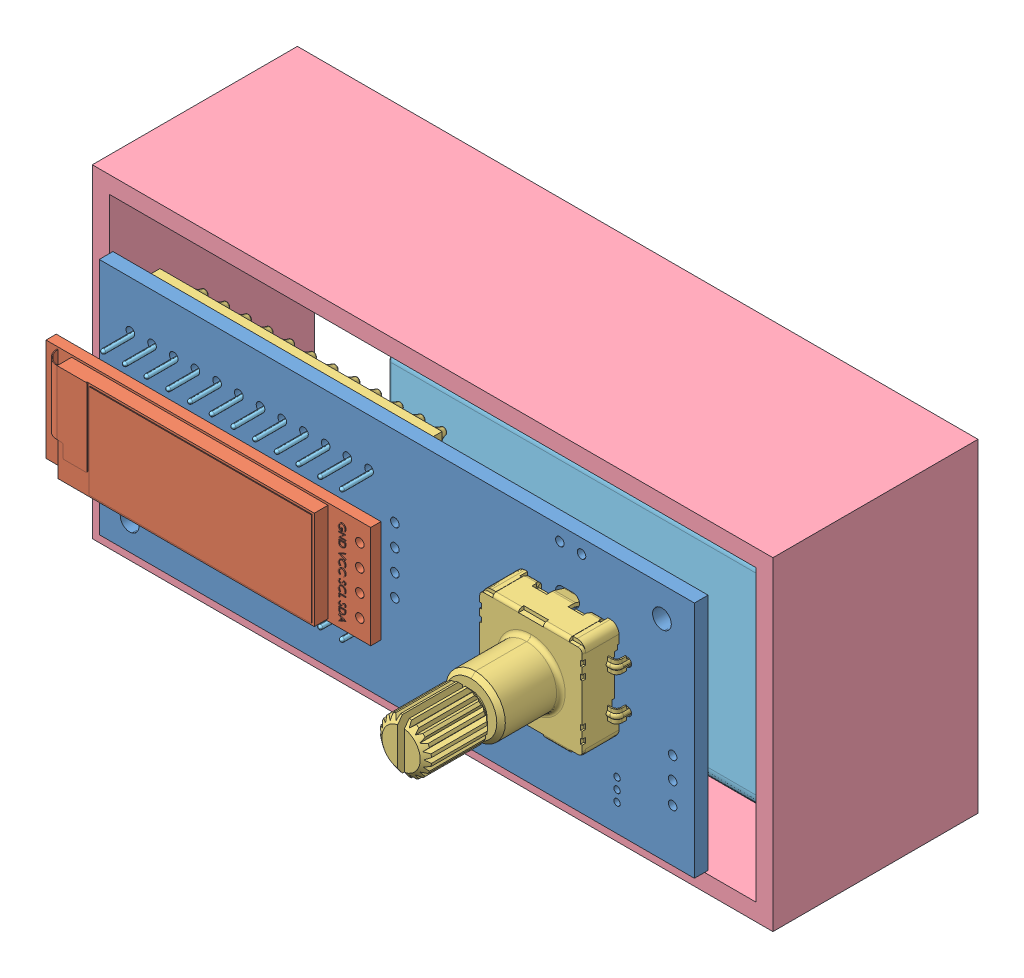
SolidWorks assembly IntervalometerFullAssembly, configuration Default. Lengths in mm.
Overall size (79.65 37.9 47.73).
70 component instances, 27 part files, 2 mates.
Components (placement in the parent):
- BoardAssembly-1: BoardAssembly [Default] at (-53.0981 -17.4336 -57.1402) size (71.78 27.9 29.29)
  - CameraIntervalometer.step-1: CameraIntervalometer.step [Default] at (-116.9591 121.2017 48.7284) size (69.65 27.9 1.6)
    - _autosave-CameraIntervalometer PCB.step-1: _autosave-CameraIntervalometer PCB.step [Default] at origin size (69.65 27.9 1.6)
  - 128x32-OLED-1: 128x32-OLED [Default] at (13.1078 38.9667 53.2284) x (-1 0 0) z (0 0 1) size (38 12 2.96)
  - ARDUINO PRO MICRO.IGS-1: ARDUINO PRO MICRO.IGS [Default] at (0.0509 46.4031 44.8284) x (1 0 0) z (0 1 0) size (34.6 13.31 17.79)
    - micro board.IGS-1: micro board.IGS [Default] at origin size (33.03 3.11 17.79)
    - MICRO_stackable header 12.IGS-1: MICRO_stackable header 12.IGS [Default] at (0 -3.9 0) size (30.49 2.91 2.55)
    - MICRO_stackable header 12.IGS-2: MICRO_stackable header 12.IGS [Default] at (0 -3.9 -15.24) size (30.49 2.91 2.55)
    - MICRO_stackable header pin.IGS-1: MICRO_stackable header pin.IGS [Default] x (0.999996 0 0.00266) z (-0.00266 0 0.999996) size (1.71 11.9 1.71)
    - MICRO_stackable header pin.IGS-2: MICRO_stackable header pin.IGS [Default] at (2.54 0 0) x (0.999996 0 0.00266) z (-0.00266 0 0.999996) size (1.71 11.9 1.71)
    - MICRO_stackable header pin.IGS-3: MICRO_stackable header pin.IGS [Default] at (5.08 0 0) x (0.999996 0 0.00266) z (-0.00266 0 0.999996) size (1.71 11.9 1.71)
    - MICRO_stackable header pin.IGS-4: MICRO_stackable header pin.IGS [Default] at (7.62 0 0) x (0.999996 0 0.00266) z (-0.00266 0 0.999996) size (1.71 11.9 1.71)
    - MICRO_stackable header pin.IGS-5: MICRO_stackable header pin.IGS [Default] at (10.16 0 0) x (0.999996 0 0.00266) z (-0.00266 0 0.999996) size (1.71 11.9 1.71)
    - MICRO_stackable header pin.IGS-6: MICRO_stackable header pin.IGS [Default] at (12.7 0 0) x (0.999996 0 0.00266) z (-0.00266 0 0.999996) size (1.71 11.9 1.71)
    - MICRO_stackable header pin.IGS-7: MICRO_stackable header pin.IGS [Default] at (15.24 0 0) x (0.999996 0 0.00266) z (-0.00266 0 0.999996) size (1.71 11.9 1.71)
    - MICRO_stackable header pin.IGS-8: MICRO_stackable header pin.IGS [Default] at (17.78 0 0) x (0.999996 0 0.00266) z (-0.00266 0 0.999996) size (1.71 11.9 1.71)
    - MICRO_stackable header pin.IGS-9: MICRO_stackable header pin.IGS [Default] at (20.32 0 0) x (0.999996 0 0.00266) z (-0.00266 0 0.999996) size (1.71 11.9 1.71)
    - MICRO_stackable header pin.IGS-10: MICRO_stackable header pin.IGS [Default] at (22.86 0 0) x (0.999996 0 0.00266) z (-0.00266 0 0.999996) size (1.71 11.9 1.71)
    - MICRO_stackable header pin.IGS-11: MICRO_stackable header pin.IGS [Default] at (25.4 0 0) x (0.999996 0 0.00266) z (-0.00266 0 0.999996) size (1.71 11.9 1.71)
    - MICRO_stackable header pin.IGS-12: MICRO_stackable header pin.IGS [Default] at (27.94 0 0) x (0.999996 0 0.00266) z (-0.00266 0 0.999996) size (1.71 11.9 1.71)
    - MICRO_stackable header pin.IGS-13: MICRO_stackable header pin.IGS [Default] at (0 0 -15.24) x (0.999996 0 0.00266) z (-0.00266 0 0.999996) size (1.71 11.9 1.71)
    - MICRO_stackable header pin.IGS-14: MICRO_stackable header pin.IGS [Default] at (2.54 0 -15.24) x (0.999996 0 0.00266) z (-0.00266 0 0.999996) size (1.71 11.9 1.71)
    - MICRO_stackable header pin.IGS-15: MICRO_stackable header pin.IGS [Default] at (5.08 0 -15.24) x (0.999996 0 0.00266) z (-0.00266 0 0.999996) size (1.71 11.9 1.71)
    - MICRO_stackable header pin.IGS-16: MICRO_stackable header pin.IGS [Default] at (7.62 0 -15.24) x (0.999996 0 0.00266) z (-0.00266 0 0.999996) size (1.71 11.9 1.71)
    - MICRO_stackable header pin.IGS-17: MICRO_stackable header pin.IGS [Default] at (10.16 0 -15.24) x (0.999996 0 0.00266) z (-0.00266 0 0.999996) size (1.71 11.9 1.71)
    - MICRO_stackable header pin.IGS-18: MICRO_stackable header pin.IGS [Default] at (12.7 0 -15.24) x (0.999996 0 0.00266) z (-0.00266 0 0.999996) size (1.71 11.9 1.71)
    - MICRO_stackable header pin.IGS-19: MICRO_stackable header pin.IGS [Default] at (15.24 0 -15.24) x (0.999996 0 0.00266) z (-0.00266 0 0.999996) size (1.71 11.9 1.71)
    - MICRO_stackable header pin.IGS-20: MICRO_stackable header pin.IGS [Default] at (17.78 0 -15.24) x (0.999996 0 0.00266) z (-0.00266 0 0.999996) size (1.71 11.9 1.71)
    - MICRO_stackable header pin.IGS-21: MICRO_stackable header pin.IGS [Default] at (20.32 0 -15.24) x (0.999996 0 0.00266) z (-0.00266 0 0.999996) size (1.71 11.9 1.71)
    - MICRO_stackable header pin.IGS-22: MICRO_stackable header pin.IGS [Default] at (22.86 0 -15.24) x (0.999996 0 0.00266) z (-0.00266 0 0.999996) size (1.71 11.9 1.71)
    - MICRO_stackable header pin.IGS-23: MICRO_stackable header pin.IGS [Default] at (25.4 0 -15.24) x (0.999996 0 0.00266) z (-0.00266 0 0.999996) size (1.71 11.9 1.71)
    - MICRO_stackable header pin.IGS-24: MICRO_stackable header pin.IGS [Default] at (27.94 0 -15.24) x (0.999996 0 0.00266) z (-0.00266 0 0.999996) size (1.71 11.9 1.71)
    - micro usb shell.IGS-1: micro usb shell.IGS [Default] at (-4.75 1.85 -7.62) x (0 0 1) z (-1 0 0) size (8.01 2.96 5.64)
    - micro usb internal.IGS-1: micro usb internal.IGS [Default] at (-4.75 1.6 -7.62) x (0 0 1) z (-1 0 0) size (6.91 2.91 4.01)
    - micro usb contact.IGS-1: micro usb contact.IGS [Default] at (-4.65 1.6 -6.32) x (0 0 1) z (-1 0 0) size (0.21 1.31 4.41)
    - micro usb contact.IGS-2: micro usb contact.IGS [Default] at (-4.65 1.6 -6.97) x (0 0 1) z (-1 0 0) size (0.21 1.31 4.41)
    - micro usb contact.IGS-3: micro usb contact.IGS [Default] at (-4.65 1.6 -7.62) x (0 0 1) z (-1 0 0) size (0.21 1.31 4.41)
    - micro usb contact.IGS-4: micro usb contact.IGS [Default] at (-4.65 1.6 -8.27) x (0 0 1) z (-1 0 0) size (0.21 1.31 4.41)
    - micro usb contact.IGS-5: micro usb contact.IGS [Default] at (-4.65 1.6 -8.92) x (0 0 1) z (-1 0 0) size (0.21 1.31 4.41)
    - atmega32U4.IGS-1: atmega32U4.IGS [Default] at (15.24 1.62 -7.62) x (-0.707107 0 0.707107) z (-0.707107 0 -0.707107) size (7.24 1.03 7.24)
    - MICRO_cap106C.IGS-1: MICRO_cap106C.IGS [Default] at (7.3558 1.6 -11.4427) x (0 0 -1) z (1 0 0) size (1.71 1.82 4.04)
    - MICRO_cap106C.IGS-2: MICRO_cap106C.IGS [Default] at (7.3558 1.6 -3.7973) x (0 0 -1) z (1 0 0) size (1.71 1.82 4.04)
    - micro_crystal 5x3.IGS-1: micro_crystal 5x3.IGS [Default] at (27.051 1.65 -7.62) x (0 0 -1) z (1 0 0) size (5.71 1.01 3.41)
    - micro_MIC5219.IGS-1: micro_MIC5219.IGS [Default] at (7.366 1.6 -7.874) x (-1 0 0) z (0 0 -1) size (2.91 1.21 3.7)
    - MICRO_603 resistor 103.IGS-1: MICRO_603 resistor 103.IGS [Default] at (1.27 1.6 -3.81) x (0 0 1) z (-1 0 0) size (2.37 0.62 1.03)
    - MICRO_603 resistor 102.IGS-1: MICRO_603 resistor 102.IGS [Default] at (2.667 1.6 -3.81) x (0 0 1) z (-1 0 0) size (2.37 0.63 1.03)
    - MICRO_603 resistor 22.IGS-1: MICRO_603 resistor 22.IGS [Default] at (1.27 1.6 -11.43) x (0 0 1) z (-1 0 0) size (2.37 0.63 1.03)
    - MICRO_603 resistor 22.IGS-2: MICRO_603 resistor 22.IGS [Default] at (2.667 1.6 -11.43) x (0 0 1) z (-1 0 0) size (2.37 0.63 1.03)
    - MICRO_PTC-1206.IGS-1: MICRO_PTC-1206.IGS [Default] at (4.445 1.6 -7.62) x (0 0 1) z (-1 0 0) size (3.85 1.18 1.83)
    - MICRO_603 resistor 331.IGS-1: MICRO_603 resistor 331.IGS [Default] at (27.432 1.6 -11.938) size (2.37 0.62 1.03)
    - MICRO_603 resistor 331.IGS-2: MICRO_603 resistor 331.IGS [Default] at (27.432 1.6 -3.302) size (2.37 0.62 1.03)
    - MICRO_603 cap on pad.IGS-1: MICRO_603 cap on pad.IGS [Default] at (24.384 1.6 -9.398) x (0 0 1) z (-1 0 0) size (2.77 0.91 1.03)
    - MICRO_603 cap on pad.IGS-2: MICRO_603 cap on pad.IGS [Default] at (21.336 1.6 -11.938) size (2.77 0.91 1.03)
    - MICRO_603 cap on pad.IGS-3: MICRO_603 cap on pad.IGS [Default] at (24.384 1.6 -5.715) x (0 0 1) z (-1 0 0) size (2.77 0.91 1.03)
    - MICRO_603 cap on pad.IGS-4: MICRO_603 cap on pad.IGS [Default] at (21.336 1.6 -3.1877) size (2.77 0.91 1.03)
    - MICRO_603 cap on pad.IGS-5: MICRO_603 cap on pad.IGS [Default] at (11.0744 1.6 -3.5839) x (0 0 -1) z (1 0 0) size (2.77 0.91 1.03)
    - MICRO_603 cap on pad.IGS-6: MICRO_603 cap on pad.IGS [Default] at (10.6528 1.6 -11.4681) x (0 0 1) z (-1 0 0) size (2.77 0.91 1.03)
    - MICRO_603 cap on pad.IGS-7: MICRO_603 cap on pad.IGS [Default] at (4.1758 1.6 -11.43) x (0 0 -1) z (1 0 0) size (2.77 0.91 1.03)
    - SOD 323.IGS-1: SOD 323.IGS [Default] at (2.6416 1.6 -7.62) x (0 0 1) z (-1 0 0) size (2.94 1.12 1.26)
    - MICRO_led.IGS-1: MICRO_led.IGS [Default] at (24.384 1.62 -2.6907) size (2.53 0.73 0.81)
    - MICRO_led.IGS-2: MICRO_led.IGS [Default] at (24.384 1.62 -11.938) size (2.53 0.73 0.81)
    - MICRO_led.IGS-3: MICRO_led.IGS [Default] at (4.1046 1.62 -3.81) x (0 0 -1) z (1 0 0) size (2.53 0.73 0.81)
  - EC11 Rotary Encoder Dode Switch-15mm .step-1: EC11 Rotary Encoder Dode Switch-15mm .step [Default] at (51.1018 39.773 50.3653) x (0 -1 0) z (0 0 1) size (11.71 14.96 23.16)
- Part23^IntervalometerFullAssembly-1: Part23^IntervalometerFullAssembly [Default] at origin size (79.65 37.9 24) (virtual)
- Part24^IntervalometerFullAssembly-1: Part24^IntervalometerFullAssembly [Default] at origin (virtual)
- Part25^IntervalometerFullAssembly-1: Part25^IntervalometerFullAssembly [Default] at origin (virtual)
- 9V_Batterie.STEP-1: 9V_Batterie.STEP [Default] at (-32.3509 20.7339 -24.9293) x (0 -1 0) z (1 0 0) size (26.5 17.5 49.01)
  - Corps Batterie.STEP-1: Corps Batterie.STEP [Default] at origin size (26.5 17.5 45.5)
  - Connecteur femelle Batterie 9V.STEP-1: Connecteur femelle Batterie 9V.STEP [Default] at (-6.5 0 0.5) x (1 0 0) z (0 1 0) size (8.01 5.32 8.38)
  - Connecteur male Batterie 9V.STEP-1: Connecteur male Batterie 9V.STEP [Default] at (6.5 0 0.5) x (0.847736 0.530419 0) z (-0.530419 0.847736 0) size (7.01 4.82 7.01)
Mates (geometry in assembly coordinates):
- Parallel1: parallel anti-aligned: plane of 9V_Batterie.STEP-1/Corps Batterie.STEP-1 through (13.1491 20.7339 -33.6793) normal (0 0 -1)
- Parallel2: parallel anti-aligned: plane of 9V_Batterie.STEP-1/Corps Batterie.STEP-1 through (-31.8509 9.1339 -17.9293) normal (-1 0 0)
